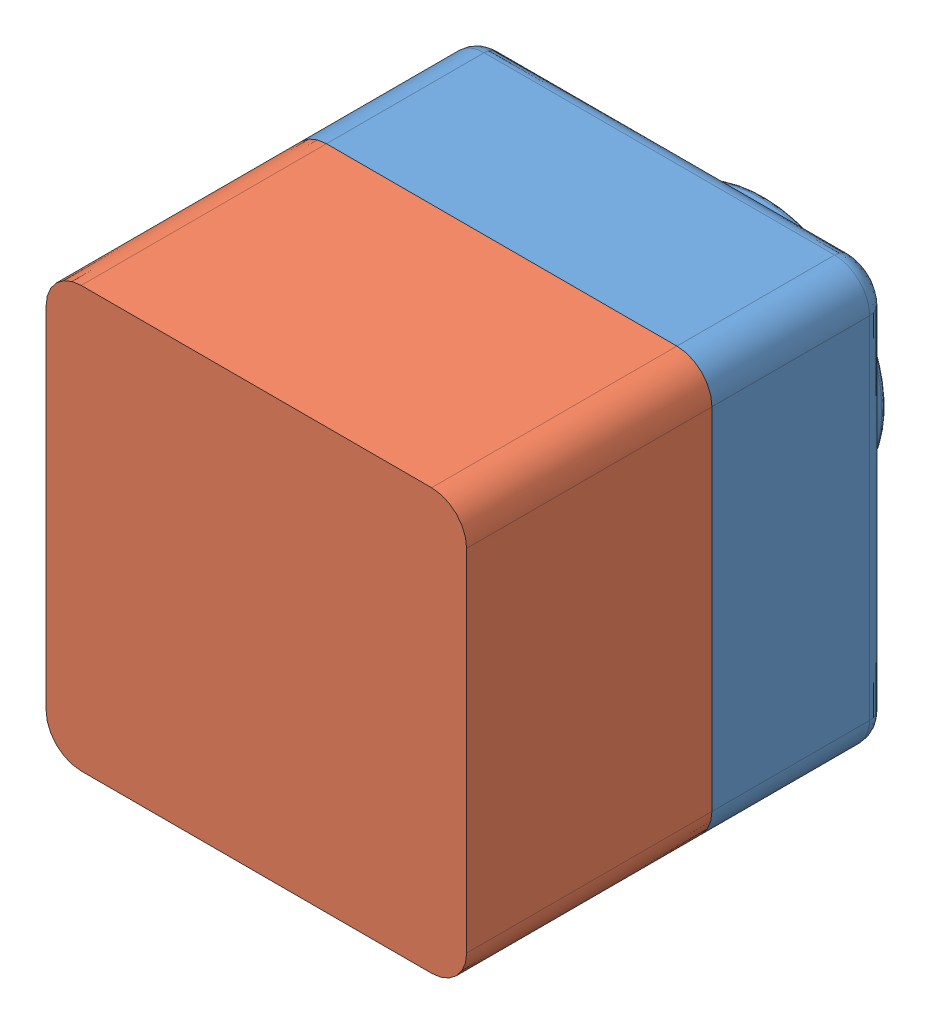
SolidWorks assembly tutor_assem, configuration Default. Lengths in mm.
Overall size (120 120 145).
2 component instances, 2 part files, 3 mates.
Components (placement in the parent):
- tutor_1-1: tutor_1 [Default] at (7.255 53.5673 118.0704) size (120 120 75)
- tutor_2-1: tutor_2 [Default] at (127.255 53.5673 238.0704) x (-1 0 0) z (0 0 -1) size (120 120 90)
Mates (geometry in assembly coordinates):
- Coincident2: coincident aligned: plane of tutor 1-1 through (127.255 53.5673 168.0704) normal (1 0 0); plane of tutor 2-1 through (127.255 53.5673 148.0704) normal (1 0 0)
- Coincident3: coincident anti-aligned: plane of tutor 1-1 through (7.255 53.5673 168.0704) normal (0 0 1); plane of tutor 2-1 through (117.255 63.5673 168.0704) normal (0 0 -1)
- Coincident5: coincident aligned: plane of tutor 1-1 through (7.255 173.5673 168.0704) normal (0 1 0); plane of tutor 2-1 through (127.255 173.5673 148.0704) normal (0 1 0)
